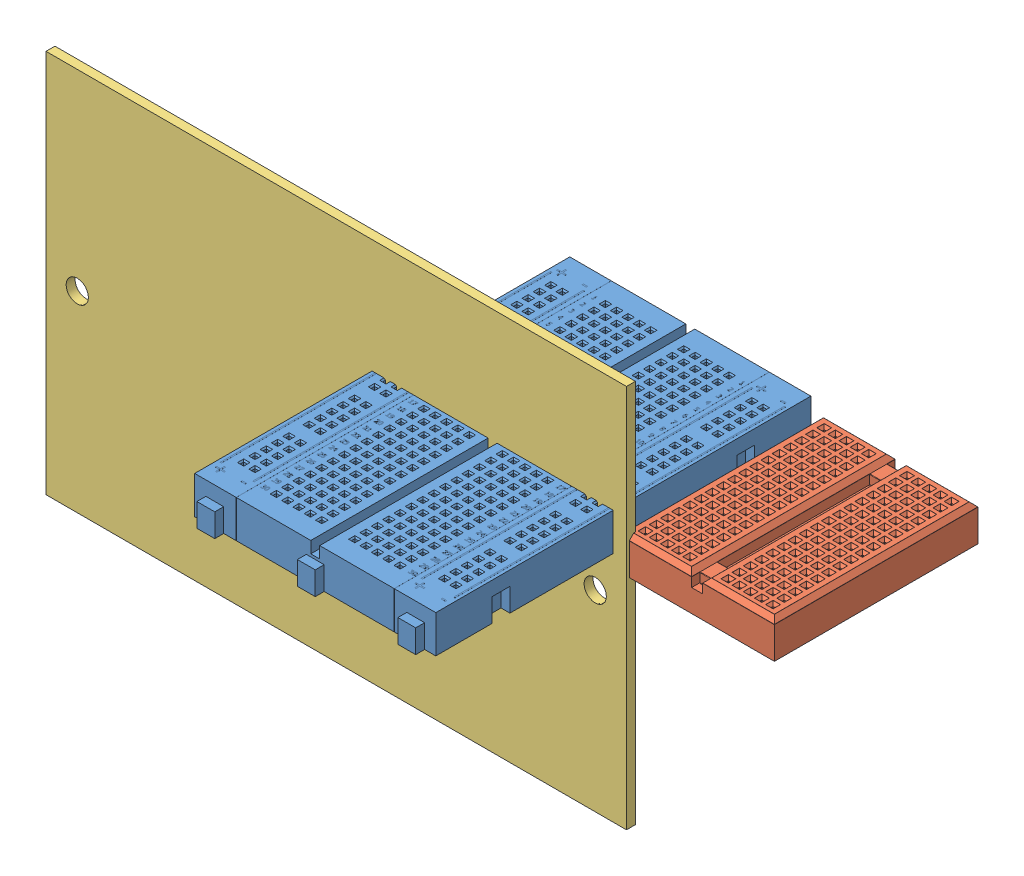
SolidWorks assembly breadboard setup, configuration Default. Lengths in mm.
Overall size (145 84 87.95).
3 component instances, 3 part files, 0 mates.
Components (placement in the parent):
- halfBreadboard 400.stp-1: halfBreadboard 400.stp [Default] at (19.9365 64.6463 59.0024) size (56 8.41 86)
- MiniBreadboard-1: MiniBreadboard [Default] at (92.1148 61.152 79.8542) size (34.6 8.15 45.6)
- breadboard_mount-1: breadboard_mount [Default] at (11.9149 55.5433 101.2797) size (130 86 2)
